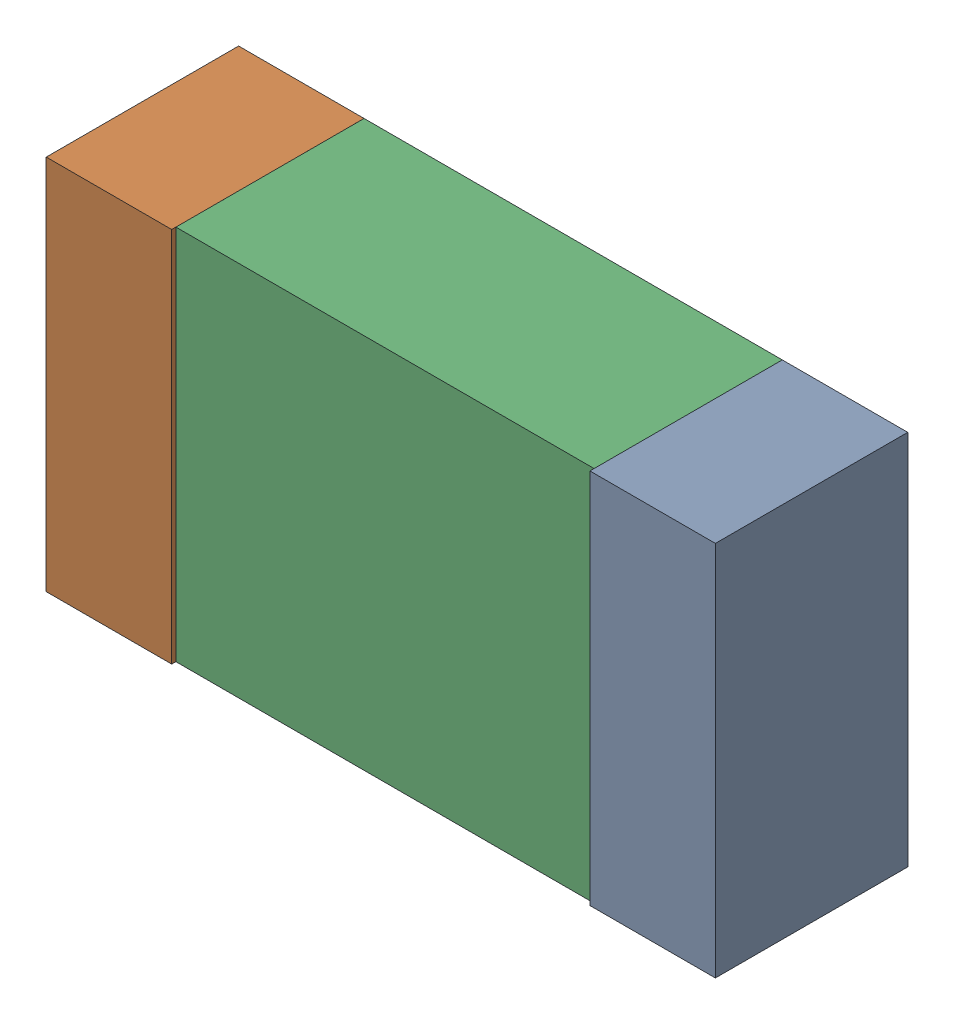
SolidWorks assembly C19, configuration Default. Lengths in mm.
Overall size (1.6 0.9 0.46).
6 component instances, 2 part files, 0 mates.
Components (placement in the parent):
- 870942080-1: 870942080 [Default] at (62.892 37.465 0) size (0.3 0.9 0.46)
  - Extruded_15-1: Extruded_15 [Default] at origin size (0.3 0.9 0.46)
- 870942080-2: 870942080 [Default] at (61.592 37.465 0) size (0.3 0.9 0.46)
  - Extruded_15-1: Extruded_15 [Default] at origin size (0.3 0.9 0.46)
- 870942240-1: 870942240 [Default] at (62.242 37.465 0) size (1 0.9 0.45)
  - Extruded_14-1: Extruded_14 [Default] at origin size (1 0.9 0.45)
